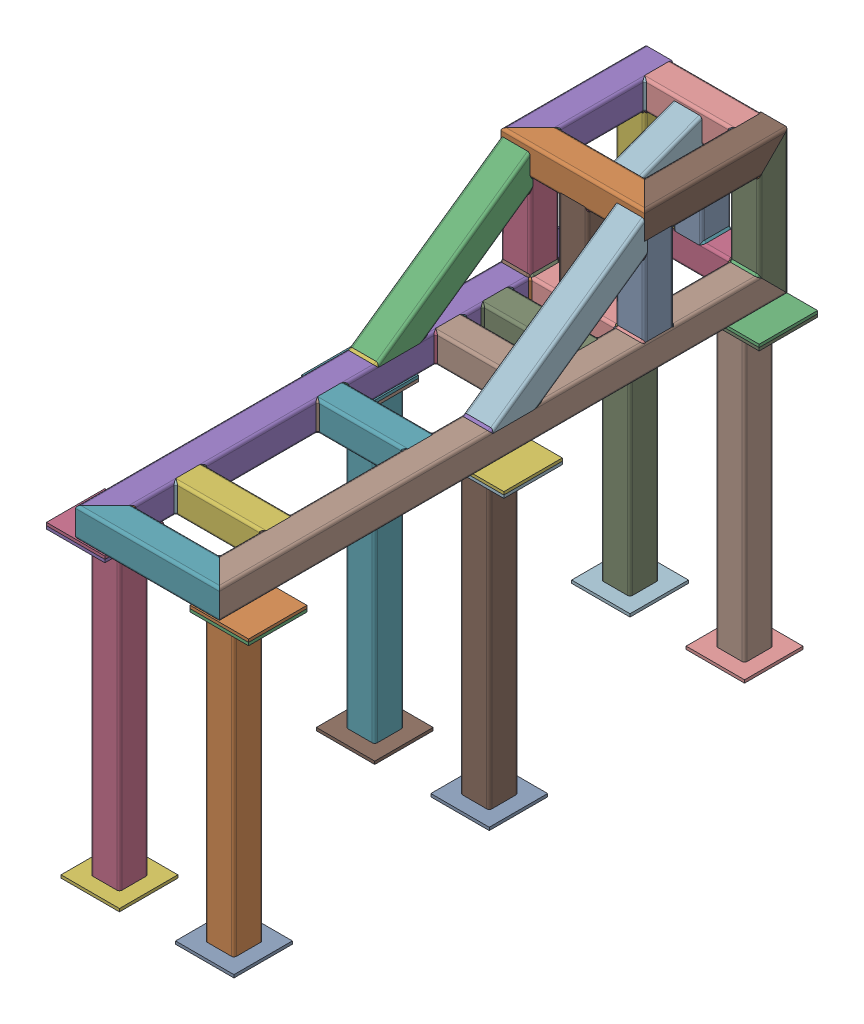
SolidWorks assembly Proyecto Banco de pruebas, configuration Default. Lengths in mm.
Overall size (346 761 974).
28 component instances, 3 part files, 36 mates.
Components (placement in the parent):
- base banco de pruebas-1: base banco de pruebas [Default<As Machined>] at origin size (246.01 246 974)
- placa banco de pruebas-1: placa banco de pruebas [Default] at (12.5413 -38 585.8917) size (100 5 100)
- placa banco de pruebas-2: placa banco de pruebas [Default] at (12.5413 -38 -288.1083) size (100 5 100)
- placa banco de pruebas-3: placa banco de pruebas [Default] at (-233.4587 -38 585.8917) size (100 5 100)
- placa banco de pruebas-4: placa banco de pruebas [Default] at (-233.4587 -38 -288.1083) size (100 5 100)
- placa banco de pruebas-6: placa banco de pruebas [Default] at (12.5413 -38 148.8917) size (100 5 100)
- placa banco de pruebas-7: placa banco de pruebas [Default] at (-233.4587 -38 148.8917) size (100 5 100)
- castillo con placa-1: castillo con placa [Default] at (347.5608 -98.8624 -394.7956) x (0 0 1) z (-1 0 0) size (100 510 125)
  - castillo-1: castillo [Default<As Machined>] at (56.6874 -444.1376 310.0195) size (50 500 50)
  - placa banco de pruebas-1: placa banco de pruebas [Default] at (6.6874 55.8624 335.0195) size (100 5 100)
  - placa banco de pruebas-2: placa banco de pruebas [Default] at (6.6874 -449.1376 260.0195) x (0 0 1) z (-1 0 0) size (100 5 100)
- castillo con placa-2: castillo con placa [Default] at (347.5608 -98.8624 42.2044) x (0 0 1) z (-1 0 0) size (100 510 125)
  - castillo-1: castillo [Default<As Machined>] at (56.6874 -444.1376 310.0195) size (50 500 50)
  - placa banco de pruebas-1: placa banco de pruebas [Default] at (6.6874 55.8624 335.0195) size (100 5 100)
  - placa banco de pruebas-2: placa banco de pruebas [Default] at (6.6874 -449.1376 260.0195) x (0 0 1) z (-1 0 0) size (100 5 100)
- castillo-2: castillo [Default<As Machined>] at (37.5413 -543 535.8917) x (0 0 1) z (-1 0 0) size (50 500 50)
- placa banco de pruebas-8: placa banco de pruebas [Default] at (12.5413 -43 485.8917) x (0 0 1) z (-1 0 0) size (100 5 100)
- castillo con placa-3: castillo con placa [Default] at (-468.4783 -98.8624 592.5791) x (0 0 -1) z (1 0 0) size (100 510 125)
  - castillo-1: castillo [Default<As Machined>] at (56.6874 -444.1376 310.0195) size (50 500 50)
  - placa banco de pruebas-1: placa banco de pruebas [Default] at (6.6874 55.8624 335.0195) size (100 5 100)
  - placa banco de pruebas-2: placa banco de pruebas [Default] at (6.6874 -449.1376 260.0195) x (0 0 1) z (-1 0 0) size (100 5 100)
- castillo-3: castillo [Default<As Machined>] at (-158.4587 -543 98.8917) x (0 0 -1) z (1 0 0) size (50 500 50)
- placa banco de pruebas-9: placa banco de pruebas [Default] at (-133.4587 -43 148.8917) x (0 0 -1) z (1 0 0) size (100 5 100)
- castillo-4: castillo [Default<As Machined>] at (-158.4587 -543 -338.1083) x (0 0 -1) z (1 0 0) size (50 500 50)
- placa banco de pruebas-10: placa banco de pruebas [Default] at (-133.4587 -43 -288.1083) x (0 0 -1) z (1 0 0) size (100 5 100)
- placa banco de pruebas-11: placa banco de pruebas [Default] at (-208.4587 -543 48.8917) x (1 0 0) z (0 0 -1) size (100 5 100)
- placa banco de pruebas-12: placa banco de pruebas [Default] at (-208.4587 -548 -288.1083) size (100 5 100)
- placa banco de pruebas-13: placa banco de pruebas [Default] at (87.5413 -548 485.8917) x (-1 0 0) z (0 0 -1) size (100 5 100)
Mates (geometry in assembly coordinates):
- Coincident13: coincident anti-aligned: plane of banco de pruebas (como lo llora, digo como lo quiere leo)-1 through (17.0413 -33 -363.1083) normal (0 -1 0); plane of placa banco de pruebas-2 through (12.5413 -33 -288.1083) normal (0 1 0)
- Coincident14: coincident aligned: plane of banco de pruebas (como lo llora, digo como lo quiere leo)-1 through (12.5413 12.5 -363.1083) normal (-1 0 0); plane of placa banco de pruebas-2 through (12.5413 -33 -288.1083) normal (-1 0 0)
- Coincident15: coincident aligned: plane of banco de pruebas (como lo llora, digo como lo quiere leo)-1 through (17.0413 188 -388.1083) normal (0 0 -1); plane of placa banco de pruebas-2 through (12.5413 -33 -388.1083) normal (0 0 -1)
- Coincident16: coincident anti-aligned: plane of banco de pruebas (como lo llora, digo como lo quiere leo)-1 through (-137.9587 -33 560.8917) normal (0 -1 0); plane of placa banco de pruebas-4 through (-233.4587 -33 -288.1083) normal (0 1 0)
- Coincident17: coincident aligned: plane of banco de pruebas (como lo llora, digo como lo quiere leo)-1 through (-133.4587 12.5 560.8917) normal (1 0 0); plane of placa banco de pruebas-4 through (-133.4587 -33 -288.1083) normal (1 0 0)
- Coincident18: coincident aligned: plane of banco de pruebas (como lo llora, digo como lo quiere leo)-1 through (-137.9587 -8 -388.1083) normal (0 0 -1); plane of placa banco de pruebas-4 through (-233.4587 -33 -388.1083) normal (0 0 -1)
- Coincident19: coincident anti-aligned: plane of banco de pruebas (como lo llora, digo como lo quiere leo)-1 through (-137.9587 -33 560.8917) normal (0 -1 0); plane of placa banco de pruebas-3 through (-233.4587 -33 585.8917) normal (0 1 0)
- Coincident20: coincident aligned: plane of banco de pruebas (como lo llora, digo como lo quiere leo)-1 through (-133.4587 12.5 560.8917) normal (1 0 0); plane of placa banco de pruebas-3 through (-133.4587 -33 585.8917) normal (1 0 0)
- Coincident21: coincident aligned: plane of banco de pruebas (como lo llora, digo como lo quiere leo)-1 through (37.5413 12.5 585.8917) normal (0 0 1); plane of placa banco de pruebas-3 through (-233.4587 -33 585.8917) normal (0 0 1)
- Coincident46: coincident anti-aligned: plane of banco de pruebas (como lo llora, digo como lo quiere leo)-1 through (-137.9587 -33 560.8917) normal (0 -1 0); plane of placa banco de pruebas-7 through (-233.4587 -33 148.8917) normal (0 1 0)
- Coincident47: coincident aligned: plane of banco de pruebas (como lo llora, digo como lo quiere leo)-1 through (-133.4587 12.5 560.8917) normal (1 0 0); plane of placa banco de pruebas-7 through (-133.4587 -33 148.8917) normal (1 0 0)
- Distance6: distance = 337 mm anti-aligned: plane of placa banco de pruebas-7 through (-233.4587 -33 48.8917) normal (0 0 -1); plane of placa banco de pruebas-4 through (-233.4587 -33 -288.1083) normal (0 0 1)
- Coincident50: coincident anti-aligned: plane of banco de pruebas (como lo llora, digo como lo quiere leo)-1 through (17.0413 -33 -363.1083) normal (0 -1 0); plane of placa banco de pruebas-6 through (12.5413 -33 148.8917) normal (0 1 0)
- Coincident51: coincident aligned: plane of banco de pruebas (como lo llora, digo como lo quiere leo)-1 through (12.5413 12.5 -363.1083) normal (-1 0 0); plane of placa banco de pruebas-6 through (12.5413 -33 148.8917) normal (-1 0 0)
- Coincident52: coincident aligned: plane of placa banco de pruebas-6 through (12.5413 -33 148.8917) normal (0 0 1); plane of placa banco de pruebas-7 through (-233.4587 -33 148.8917) normal (0 0 1)
- ProfileCenter3: profile center anti-aligned: plane of castillo con placa-1/placa banco de pruebas-1 through (12.5413 -38 -388.1083) normal (0 1 0); plane of placa banco de pruebas-2 through (12.5413 -38 -288.1083) normal (0 -1 0)
- Coincident57: coincident anti-aligned: plane of castillo-2 through (58.0413 -43 515.3917) normal (0 1 0); plane of placa banco de pruebas-8 through (12.5413 -43 485.8917) normal (0 -1 0)
- Coincident58: coincident aligned: plane of castillo-2 through (12.5413 -43 515.3917) normal (-1 0 0); plane of placa banco de pruebas-8 through (12.5413 -38 485.8917) normal (-1 0 0)
- Distance8: distance = 25 mm aligned: plane of castillo-2 through (17.0413 -43 510.8917) normal (0 0 -1); plane of placa banco de pruebas-8 through (12.5413 -38 485.8917) normal (0 0 -1)
- ProfileCenter4: profile center anti-aligned: plane of castillo con placa-2/placa banco de pruebas-1 through (12.5413 -38 48.8917) normal (0 1 0); plane of placa banco de pruebas-6 through (12.5413 -38 148.8917) normal (0 -1 0)
- Coincident60: coincident anti-aligned: plane of banco de pruebas (como lo llora, digo como lo quiere leo)-1 through (17.0413 -33 -363.1083) normal (0 -1 0); plane of placa banco de pruebas-1 through (12.5413 -33 585.8917) normal (0 1 0)
- Coincident62: coincident aligned: plane of banco de pruebas (como lo llora, digo como lo quiere leo)-1 through (37.5413 12.5 585.8917) normal (0 0 1); plane of placa banco de pruebas-1 through (12.5413 -33 585.8917) normal (0 0 1)
- Coincident63: coincident aligned: plane of banco de pruebas (como lo llora, digo como lo quiere leo)-1 through (12.5413 12.5 -363.1083) normal (-1 0 0); plane of placa banco de pruebas-1 through (12.5413 -33 585.8917) normal (-1 0 0)
- ProfileCenter6: profile center anti-aligned: plane of placa banco de pruebas-8 through (12.5413 -38 485.8917) normal (0 1 0); plane of placa banco de pruebas-1 through (12.5413 -38 585.8917) normal (0 -1 0)
- Coincident65: coincident anti-aligned: plane of castillo-3 through (-178.9587 -43 119.3917) normal (0 1 0); plane of placa banco de pruebas-9 through (-133.4587 -43 148.8917) normal (0 -1 0)
- Coincident66: coincident aligned: plane of castillo-3 through (-133.4587 -43 119.3917) normal (1 0 0); plane of placa banco de pruebas-9 through (-133.4587 -38 148.8917) normal (1 0 0)
- Distance9: distance = 25 mm aligned: plane of castillo-3 through (-137.9587 -43 123.8917) normal (0 0 1); plane of placa banco de pruebas-9 through (-133.4587 -38 148.8917) normal (0 0 1)
- Coincident67: coincident anti-aligned: plane of castillo-4 through (-178.9587 -43 -317.6083) normal (0 1 0); plane of placa banco de pruebas-10 through (-133.4587 -43 -288.1083) normal (0 -1 0)
- Coincident68: coincident aligned: plane of castillo-4 through (-133.4587 -43 -317.6083) normal (1 0 0); plane of placa banco de pruebas-10 through (-133.4587 -38 -288.1083) normal (1 0 0)
- Distance10: distance = 25 mm aligned: plane of castillo-4 through (-137.9587 -43 -313.1083) normal (0 0 1); plane of placa banco de pruebas-10 through (-133.4587 -38 -288.1083) normal (0 0 1)
- ProfileCenter7: profile center anti-aligned: plane of castillo con placa-3/placa banco de pruebas-1 through (-133.4587 -38 585.8917) normal (0 1 0); plane of placa banco de pruebas-3 through (-233.4587 -38 585.8917) normal (0 -1 0)
- ProfileCenter8: profile center anti-aligned: plane of placa banco de pruebas-9 through (-133.4587 -38 148.8917) normal (0 1 0); plane of placa banco de pruebas-7 through (-233.4587 -38 148.8917) normal (0 -1 0)
- ProfileCenter9: profile center anti-aligned: plane of placa banco de pruebas-10 through (-133.4587 -38 -288.1083) normal (0 1 0); plane of placa banco de pruebas-4 through (-233.4587 -38 -288.1083) normal (0 -1 0)
- ProfileCenter10: profile center anti-aligned: plane of placa banco de pruebas-11 through (-208.4587 -543 48.8917) normal (0 1 0); plane of castillo-3 through (-178.9587 -543 119.3917) normal (0 -1 0)
- ProfileCenter11: profile center anti-aligned: plane of placa banco de pruebas-12 through (-208.4587 -543 -288.1083) normal (0 1 0); plane of castillo-4 through (-178.9587 -543 -317.6083) normal (0 -1 0)
- ProfileCenter12: profile center anti-aligned: plane of placa banco de pruebas-13 through (87.5413 -543 485.8917) normal (0 1 0); plane of castillo-2 through (58.0413 -543 515.3917) normal (0 -1 0)
